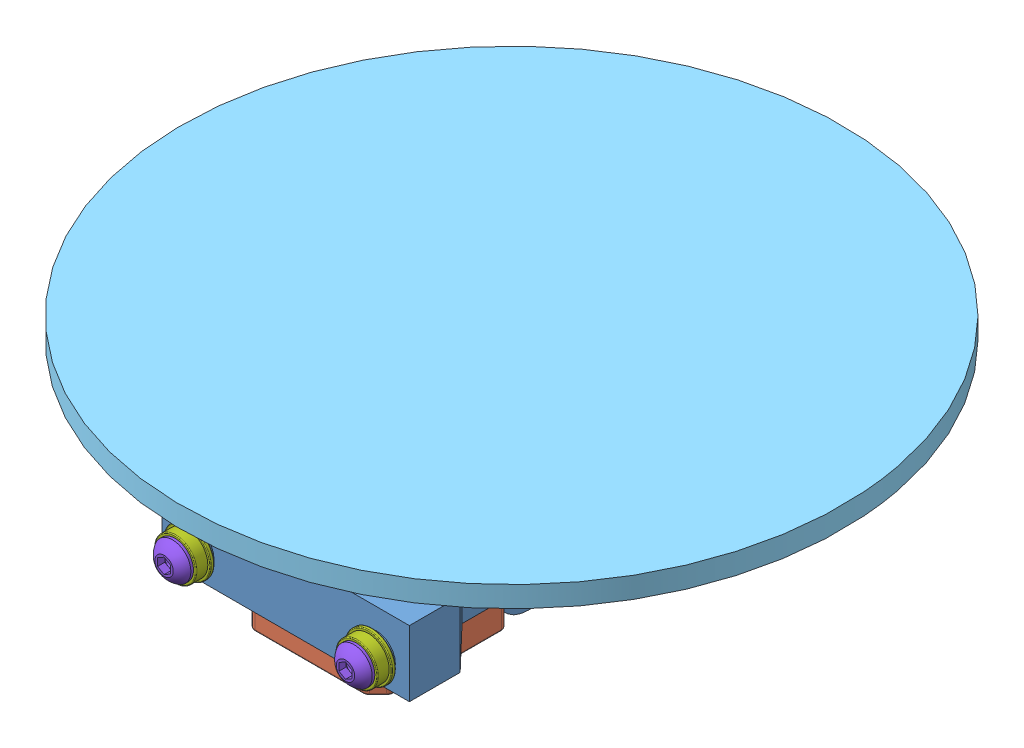
SolidWorks assembly Cart, configuration Default. Lengths in mm.
Overall size (224.42 72.46 224.42).
21 component instances, 9 part files, 34 mates.
Components (placement in the parent):
- Cart_base-1: Cart_base [Default] at (5.4308 73.0181 37.6181) size (75 44 139.54)
- NEMA_17_PHB42S20-410-TB-1: NEMA_17_PHB42S20-410-TB [Default] at (27.9308 1160.0181 151.3181) x (0 0 1) z (0 -1 0) size (42.3 42.3 43.3)
- Gear-1: Gear [Default] at (42.9308 107.2581 146.6181) x (-0.116014 0 -0.993248) z (0 -1 0) size (44.15 44.15 25.24)
- Gear - Copy-4: Gear - Copy [Default] at (42.9308 97.2581 106.1181) x (-0.799247 0 0.601003) z (0 1 0) size (44.15 44.15 13.5)
- Disc-1: Disc [Default] at (42.9308 121.4821 106.1181) x (0.13069 0 0.991423) z (0.991423 0 -0.13069) size (200 6.35 200)
- socket countersunk head screw_am-1: socket countersunk head screw_am [B18.3.5M - 3 x 0.5 x 30 Socket FCHS  -- 30N] at (58.4308 93.7781 162.1181) x (0 -1 0) z (-0.022228 0 0.999753) size (30 5.35 5.35)
- socket countersunk head screw_am-2: socket countersunk head screw_am [B18.3.5M - 3 x 0.5 x 30 Socket FCHS  -- 30N] at (58.4308 93.7781 131.1181) x (0 -1 0) z (-0.024735 0 0.999694) size (30 5.35 5.35)
- socket countersunk head screw_am-3: socket countersunk head screw_am [B18.3.5M - 3 x 0.5 x 30 Socket FCHS  -- 30N] at (27.4308 93.7781 162.1181) x (0 -1 0) z (0.002833 0 0.999996) size (30 5.35 5.35)
- socket countersunk head screw_am-4: socket countersunk head screw_am [B18.3.5M - 3 x 0.5 x 30 Socket FCHS  -- 30N] at (27.4308 93.7781 131.1181) x (0 -1 0) z (0.022473 0 0.999747) size (30 5.35 5.35)
- Flanged_0.25x0.5-1: Flanged_0.25x0.5 [Default] at (70.4308 80.8921 36.3481) x (0.805459 0.592651 0) z (-0.592651 0.805459 0) size (14.29 4.76 14.29)
- Flanged_0.25x0.5-2: Flanged_0.25x0.5 [Default] at (70.4308 80.8921 175.8881) x (0.805459 0.592651 0) z (0.592651 -0.805459 0) size (14.29 4.76 14.29)
- Flanged_0.25x0.5-3: Flanged_0.25x0.5 [Default] at (15.4308 80.8921 36.3481) x (0.998389 0.056737 0) z (-0.056737 0.998389 0) size (14.29 4.76 14.29)
- Flanged_0.25x0.5-4: Flanged_0.25x0.5 [Default] at (15.4308 80.8921 175.8881) x (0.998389 0.056737 0) z (0.056737 -0.998389 0) size (14.29 4.76 14.29)
- Flanged_0.25x0.5-5: Flanged_0.25x0.5 [Default] at (42.9308 96.0516 106.1181) size (14.29 4.76 14.29)
- Flanged_0.25x0.5-6: Flanged_0.25x0.5 [Default] at (42.9308 108.4646 106.1181) x (-0.194861 0 -0.980831) z (-0.980831 0 0.194861) size (14.29 4.76 14.29)
- socket button head cap screw_ai-2: socket button head cap screw_ai [SBHCSCREW 0.19-32x0.25-HX-N] at (42.9308 111.03 106.1181) x (0 -1 0) z (0 0 1) size (8.92 9.17 9.17)
- socket button head cap screw_ai-4: socket button head cap screw_ai [SBHCSCREW 0.25-20x0.25-HX-N] at (70.4308 80.8921 184.0034) x (0 0 -1) z (1 0 0) size (9.7 11.1 11.1)
- socket button head cap screw_ai-5: socket button head cap screw_ai [SBHCSCREW 0.25-20x0.25-HX-N] at (15.4308 80.8921 184.0034) x (0 0 -1) z (1 0 0) size (9.7 11.1 11.1)
- socket button head cap screw_ai-6: socket button head cap screw_ai [SBHCSCREW 0.25-20x0.25-HX-N] at (70.4308 80.8921 28.2328) x (0 0 1) z (-1 0 0) size (9.7 11.1 11.1)
- socket button head cap screw_ai-7: socket button head cap screw_ai [SBHCSCREW 0.25-20x0.25-HX-N] at (15.4308 80.8921 28.2328) x (0 0 1) z (-1 0 0) size (9.7 11.1 11.1)
- Disc_adapter-1: Disc_adapter [Default] at (42.9308 107.2581 106.1181) size (30.05 10.92 30.05)
Mates (geometry in assembly coordinates):
- Coincident1: coincident anti-aligned: plane of Cart_base-1 through (5.4308 80.0181 37.6181) normal (0 -1 0); plane of NEMA_17_PHB42S20-410-TB-1 through (42.9308 80.0181 146.6181) normal (0 1 0)
- Concentric1: concentric anti-aligned: cylinder of Cart_base-1 through (42.9308 93.0181 146.6181) axis (0 -1 0) radius 6.4135; cylinder of NEMA_17_PHB42S20-410-TB-1 through (42.9308 82.0181 146.6181) axis (0 1 0) radius 2.5
- Concentric2: concentric aligned: cylinder of Cart_base-1 through (58.4308 93.0181 162.1181) axis (0 -1 0) radius 1.6; cylinder of NEMA_17_PHB42S20-410-TB-1 through (58.4308 93.0181 162.1181) axis (0 -1 0) radius 1.25
- Concentric7: concentric anti-aligned: cylinder of NEMA_17_PHB42S20-410-TB-1 through (42.9308 82.0181 146.6181) axis (0 1 0) radius 2.5; cylinder of Gear-1 through (42.9308 107.2581 146.6181) axis (0 -1 0) radius 2.625
- Coincident18: coincident aligned: plane of Gear-1 through (42.9308 97.2581 146.6181) normal (0 -1 0); plane of Gear - Copy-4 through (42.9308 97.2581 106.1181) normal (0 -1 0)
- Coincident20: coincident aligned: cone of Cart_base-1 through (58.4308 93.0181 162.1181) axis (0 -1 0); cone of socket countersunk head screw_am-1 through (58.4308 93.0931 162.1181) axis (0 -1 0)
- Coincident21: coincident aligned: cone of Cart_base-1 through (58.4308 93.0181 131.1181) axis (0 -1 0); cone of socket countersunk head screw_am-2 through (58.4308 93.0931 131.1181) axis (0 -1 0)
- Coincident22: coincident aligned: cone of Cart_base-1 through (27.4308 93.0181 162.1181) axis (0 -1 0); cone of socket countersunk head screw_am-3 through (27.4308 93.0931 162.1181) axis (0 -1 0)
- Coincident23: coincident aligned: cone of Cart_base-1 through (27.4308 93.0181 131.1181) axis (0 -1 0); cone of socket countersunk head screw_am-4 through (27.4308 93.0931 131.1181) axis (0 -1 0)
- Coincident24: coincident anti-aligned: plane of Cart_base-1 through (70.4308 80.8921 36.3481) normal (0 0 -1); plane of Flanged_0.25x0.5-1 through (70.4308 80.8921 36.3481) normal (0 0 1)
- Concentric25: concentric anti-aligned: cylinder of Cart_base-1 through (70.4308 80.8921 50.3181) axis (0 0 -1) radius 2.5797; cylinder of Flanged_0.25x0.5-1 through (70.4308 80.8921 31.5856) axis (0 0 1) radius 3.175
- Coincident25: coincident anti-aligned: circle of Cart_base-1; plane of Flanged_0.25x0.5-3 through (15.4308 80.8921 36.3481) normal (0 0 1)
- Concentric26: concentric anti-aligned: cylinder of Cart_base-1 through (15.4308 80.8921 50.3181) axis (0 0 -1) radius 2.5797; cylinder of Flanged_0.25x0.5-3 through (15.4308 80.8921 31.5856) axis (0 0 1) radius 3.175
- Concentric27: concentric anti-aligned: cylinder of Gear - Copy-4 through (42.9308 97.2581 106.1181) axis (0 1 0) radius 6.4135; cylinder of Flanged_0.25x0.5-5 through (42.9308 100.8141 106.1181) axis (0 -1 0) radius 6.35
- Coincident26: coincident anti-aligned: plane of Gear - Copy-4 through (42.9308 97.2581 106.1181) normal (0 -1 0); plane of Flanged_0.25x0.5-5 through (42.9308 97.2581 106.1181) normal (0 1 0)
- Concentric28: concentric aligned: cylinder of Gear - Copy-4 through (42.9308 97.2581 106.1181) axis (0 1 0) radius 6.4135; cylinder of Flanged_0.25x0.5-6 through (42.9308 103.7021 106.1181) axis (0 1 0) radius 6.35
- Coincident27: coincident anti-aligned: plane of Gear - Copy-4 through (42.9308 107.2581 106.1181) normal (0 1 0); plane of Flanged_0.25x0.5-6 through (42.9308 107.2581 106.1181) normal (0 -1 0)
- Concentric29: concentric anti-aligned: cylinder of Cart_base-1 through (42.9308 73.0181 106.1181) axis (0 1 0) radius 2.5797; cylinder of Flanged_0.25x0.5-5 through (42.9308 100.8141 106.1181) axis (0 -1 0) radius 3.175
- Concentric31: concentric aligned: cylinder of Disc-1 through (42.9308 115.1321 106.1181) axis (0 1 0) radius 100; cylinder of Flanged_0.25x0.5-6 through (42.9308 103.7021 106.1181) axis (0 1 0) radius 3.175
- Concentric32: concentric aligned: cylinder of Flanged_0.25x0.5-6 through (42.9308 103.7021 106.1181) axis (0 1 0) radius 3.175; cylinder of socket button head cap screw_ai-2 through (42.9308 111.03 106.1181) axis (0 1 0) radius 4.5847
- Coincident30: coincident anti-aligned: plane of Flanged_0.25x0.5-6 through (42.9308 108.4646 106.1181) normal (0 1 0); plane of socket button head cap screw_ai-2 through (45.3438 108.4646 106.1181) normal (0 -1 0)
- Concentric34: concentric anti-aligned: cylinder of Flanged_0.25x0.5-2 through (70.4308 80.8921 180.6506) axis (0 0 -1) radius 3.175; cylinder of socket button head cap screw_ai-4 through (70.4308 80.8921 184.0034) axis (0 0 1) radius 5.5499
- Coincident31: coincident anti-aligned: plane of Flanged_0.25x0.5-2 through (70.4308 80.8921 180.6506) normal (0 0 1); plane of socket button head cap screw_ai-4 through (70.4308 84.0671 180.6506) normal (0 0 -1)
- Concentric35: concentric anti-aligned: cylinder of Flanged_0.25x0.5-4 through (15.4308 80.8921 180.6506) axis (0 0 -1) radius 3.175; cylinder of socket button head cap screw_ai-5 through (15.4308 80.8921 184.0034) axis (0 0 1) radius 5.5499
- Coincident32: coincident anti-aligned: plane of Flanged_0.25x0.5-4 through (15.4308 80.8921 180.6506) normal (0 0 1); plane of socket button head cap screw_ai-5 through (15.4308 84.0671 180.6506) normal (0 0 -1)
- Concentric36: concentric anti-aligned: cylinder of Flanged_0.25x0.5-1 through (70.4308 80.8921 31.5856) axis (0 0 1) radius 3.175; cylinder of socket button head cap screw_ai-6 through (70.4308 80.8921 28.2328) axis (0 0 -1) radius 5.5499
- Coincident33: coincident anti-aligned: plane of Flanged_0.25x0.5-1 through (70.4308 80.8921 31.5856) normal (0 0 -1); plane of socket button head cap screw_ai-6 through (70.4308 84.0671 31.5856) normal (0 0 1)
- Concentric37: concentric anti-aligned: cylinder of Flanged_0.25x0.5-3 through (15.4308 80.8921 31.5856) axis (0 0 1) radius 3.175; cylinder of socket button head cap screw_ai-7 through (15.4308 80.8921 28.2328) axis (0 0 -1) radius 5.5499
- Coincident34: coincident anti-aligned: plane of Flanged_0.25x0.5-3 through (15.4308 80.8921 31.5856) normal (0 0 -1); plane of socket button head cap screw_ai-7 through (15.4308 84.0671 31.5856) normal (0 0 1)
- Coincident35: coincident anti-aligned: plane of NEMA_17_PHB42S20-410-TB-1 through (42.9308 82.0181 146.6181) normal (0 1 0); plane of Gear-1 through (42.9308 82.0181 146.6181) normal (0 -1 0)
- GearMate1: gear = 1 : 1 mm: cylinder of Gear-1 through (42.9308 107.2581 146.6181) axis (0 -1 0) radius 2.625; cylinder of Gear - Copy-4 through (42.9308 97.2581 106.1181) axis (0 1 0) radius 6.4135
- Coincident36: coincident anti-aligned: plane of Gear - Copy-4 through (42.9308 107.2581 106.1181) normal (0 1 0); plane of Disc_adapter-1 through (42.9308 107.2581 106.1181) normal (0 -1 0)
- Concentric38: concentric anti-aligned: cylinder of Flanged_0.25x0.5-6 through (42.9308 107.2581 106.1181) axis (0 1 0) radius 7.1437; cylinder of Disc_adapter-1 through (42.9308 118.1801 106.1181) axis (0 -1 0) radius 6.35
- Coincident37: coincident anti-aligned: plane of Disc-1 through (42.9308 115.1321 106.1181) normal (0 -1 0); plane of Disc_adapter-1 through (42.9308 115.1321 106.1181) normal (0 1 0)
